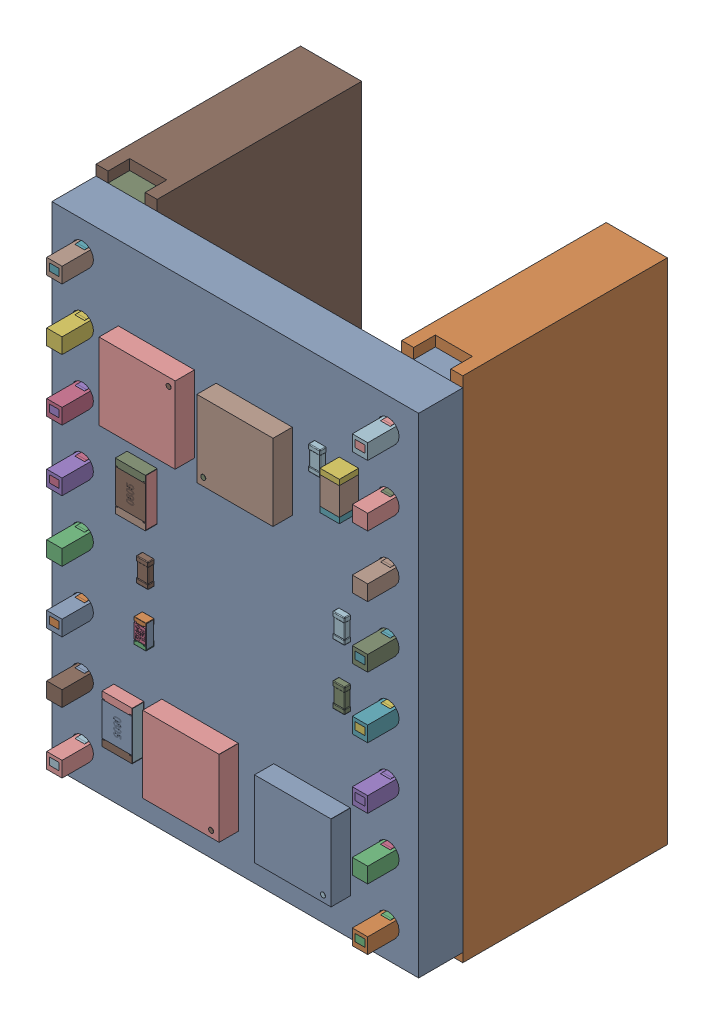
SolidWorks assembly MOTOR_DRIVER, configuration 默认. Lengths in mm.
Overall size (15.24 21.12 11.54).
82 component instances, 15 part files, 0 mates.
Components (placement in the parent):
- PCB-2-1: PCB-2 [默认] at (-7.62 10.26 8.5) x (1 0 0) z (0 0 -1) size (15.24 21.12 11.54)
  - Board-2-1: Board-2 [默认] at origin size (15.24 20.32 1.83)
    - Open CASCADE STEP translator 6.8 2.1.1-1: Open CASCADE STEP translator 6.8 2.1.1 [默认] at (0 0 -1.8339) size (15.24 20.32 1.83)
  - X-1: X [默认] at origin size (15.24 21.12 11.5)
    - DS1023-1x8SF11-1: DS1023-1x8SF11 [默认] at (13.9593 19.0061 0) x (0 -1 0) z (0 0 1) size (21.12 2.54 11.5)
    - DS1023-1x8SF11-2: DS1023-1x8SF11 [默认] at (1.2593 19.0061 0) x (0 -1 0) z (0 0 1) size (21.12 2.54 11.5)
  - U5-1: U5 [默认] at origin size (3.17 3.19 0.82)
    - 6641442208-1: 6641442208 [默认] at (8.4975 4.6 -2.7339) size (3.17 3.19 0.81)
      - Extruded-19-1: Extruded-19 [默认] at origin size (3.17 3.19 0.81)
    - 6641441808-1: 6641441808 [默认] at (7.1852 5.8608 -2.7339) x (0 -1 0) z (0 0 -1) size (0.2 0.2 0.01)
      - Cylinder-20-1: Cylinder-20 [默认] at origin size (0.2 0.2 0.01)
  - U1-1: U1 [默认] at origin size (3.19 3.17 0.82)
    - 6641441568-1: 6641441568 [默认] at (6.25 17.0875 -2.7339) size (3.19 3.17 0.81)
      - Extruded-21-1: Extruded-21 [默认] at origin size (3.19 3.17 0.81)
    - 6641441328-1: 6641441328 [默认] at (7.5108 18.3998 -2.7339) x (-1 0 0) z (0 0 -1) size (0.2 0.2 0.01)
      - Cylinder-22-1: Cylinder-22 [默认] at origin size (0.2 0.2 0.01)
  - C8-1: C8 [默认] at origin size (0.5 1 0.5)
    - User_Library-C0402-1-1: User_Library-C0402-1 [默认] at (11.385 3.6234 -1.8339) x (0 -1 0) z (0 0 -1) size (1 0.5 0.5)
  - R9-1: R9 [默认] at origin size (0.5 1 0.35)
    - User_Library-User_Library-RES0402-2-1: User_Library-User_Library-RES0402-2 [默认] at (3.9988 13.3623 -1.8339) x (0 1 0) z (0 0 -1) size (1 0.5 0.35)
  - R1-1: R1 [默认] at origin size (0.5 1 0.35)
    - User_Library-User_Library-RES0402-2-1: User_Library-User_Library-RES0402-2 [默认] at (3.1812 17.5123 0) x (0 1 0) z (0 0 1) size (1 0.5 0.35)
  - C3-1: C3 [默认] at origin size (0.5 1 0.5)
    - User_Library-C0402-1-1: User_Library-C0402-1 [默认] at (11.895 11.6466 -1.8339) x (0 1 0) z (0 0 -1) size (1 0.5 0.5)
  - U4-1: U4 [默认] at origin size (3.17 3.19 0.82)
    - 6641442208-1: 6641442208 [默认] at (4.4325 4.57 -2.7339) size (3.17 3.19 0.81)
      - Extruded-19-1: Extruded-19 [默认] at origin size (3.17 3.19 0.81)
    - 6641440128-1: 6641440128 [默认] at (5.7448 3.3092 -2.7339) x (0 1 0) z (0 0 -1) size (0.2 0.2 0.01)
      - Cylinder-23-1: Cylinder-23 [默认] at origin size (0.2 0.2 0.01)
  - U3-1: U3 [默认] at origin size (3.19 3.17 0.82)
    - 6641441328-1: 6641441328 [默认] at (12.1608 18.3998 -2.7339) x (-1 0 0) z (0 0 -1) size (0.2 0.2 0.01)
      - Cylinder-22-1: Cylinder-22 [默认] at origin size (0.2 0.2 0.01)
    - 6641441568-1: 6641441568 [默认] at (10.9 17.0875 -2.7339) size (3.19 3.17 0.81)
      - Extruded-21-1: Extruded-21 [默认] at origin size (3.19 3.17 0.81)
  - C1-1: C1 [默认] at origin size (0.5 1 0.5)
    - User_Library-C0402-1-1: User_Library-C0402-1 [默认] at (9.535 17.4466 0) x (0 1 0) z (0 0 1) size (1 0.5 0.5)
  - C2-1: C2 [默认] at origin size (1 0.5 0.5)
    - User_Library-C0402-1-1: User_Library-C0402-1 [默认] at (10.4533 16.155 0) x (-1 0 0) z (0 0 1) size (1 0.5 0.5)
  - C4-1: C4 [默认] at origin size (1 0.5 0.5)
    - User_Library-C0402-1-1: User_Library-C0402-1 [默认] at (7.7766 4.515 0) x (1 0 0) z (0 0 1) size (1 0.5 0.5)
  - C5-1: C5 [默认] at origin size (1 0.5 0.5)
    - User_Library-C0402-1-1: User_Library-C0402-1 [默认] at (11.2534 3.655 0) x (-1 0 0) z (0 0 1) size (1 0.5 0.5)
  - C7-1: C7 [默认] at origin size (0.81 1.6 0.8)
    - 6641443168-1: 6641443168 [默认] at (12.3314 3.3249 -2.6339) size (0.8 0.23 0.8)
      - Extruded-24-1: Extruded-24 [默认] at origin size (0.8 0.23 0.8)
    - 6641443168-2: 6641443168 [默认] at (12.3314 4.6949 -2.6339) size (0.8 0.23 0.8)
      - Extruded-24-1: Extruded-24 [默认] at origin size (0.8 0.23 0.8)
    - 6641442768-1: 6641442768 [默认] at (12.3313 4.0099 -2.6339) size (0.8 1.14 0.8)
      - Extruded-25-1: Extruded-25 [默认] at origin size (0.8 1.14 0.8)
  - C11-1: C11 [默认] at origin size (1 0.5 0.5)
    - User_Library-C0402-1-1: User_Library-C0402-1 [默认] at (6.8766 18.415 0) x (1 0 0) z (0 0 1) size (1 0.5 0.5)
  - C12-1: C12 [默认] at origin size (0.5 1 0.5)
    - User_Library-C0402-1-1: User_Library-C0402-1 [默认] at (3.095 3.6734 0) x (0 -1 0) z (0 0 1) size (1 0.5 0.5)
  - C13-1: C13 [默认] at origin size (0.5 1 0.5)
    - User_Library-C0402-1-1: User_Library-C0402-1 [默认] at (4.235 11.2234 -1.8339) x (0 -1 0) z (0 0 -1) size (1 0.5 0.5)
  - C14-1: C14 [默认] at origin size (0.5 1 0.5)
    - User_Library-C0402-1-1: User_Library-C0402-1 [默认] at (11.895 9.1466 -1.8339) x (0 1 0) z (0 0 -1) size (1 0.5 0.5)
  - C15-1: C15 [默认] at origin size (0.5 1 0.5)
    - User_Library-C0402-1-1: User_Library-C0402-1 [默认] at (12.485 4.8966 0) x (0 1 0) z (0 0 1) size (1 0.5 0.5)
  - J3-1: J3 [默认] at origin size (2.54 20.32 11.54)
    - 1001-8-1: 1001-8 [默认] at (1.259 19.037 0) x (0 -1 0) z (0 0 1) size (20.32 2.54 11.54)
  - J4-1: J4 [默认] at origin size (2.54 20.32 11.54)
    - 1001-8-1: 1001-8 [默认] at (13.959 19.037 0) x (0 -1 0) z (0 0 1) size (20.32 2.54 11.54)
  - R2-1: R2 [默认] at origin size (1.25 2 0.5)
    - User_Library-R_0805-1: User_Library-R_0805 [默认] at (3.19 17.0633 -1.8239) x (0 1 0) z (0 0 -1) size (2 1.25 0.5)
  - R3-1: R3 [默认] at origin size (0.5 1 0.35)
    - User_Library-User_Library-RES0402-2-1: User_Library-User_Library-RES0402-2 [默认] at (7.4488 17.1077 0) x (0 -1 0) z (0 0 1) size (1 0.5 0.35)
  - R4-1: R4 [默认] at origin size (1 0.5 0.35)
    - User_Library-User_Library-RES0402-2-1: User_Library-User_Library-RES0402-2 [默认] at (3.5377 15.3012 0) x (-1 0 0) z (0 0 1) size (1 0.5 0.35)
  - R6-1: R6 [默认] at origin size (0.5 1 0.35)
    - User_Library-User_Library-RES0402-2-1: User_Library-User_Library-RES0402-2 [默认] at (4.3312 17.5123 0) x (0 1 0) z (0 0 1) size (1 0.5 0.35)
  - R8-1: R8 [默认] at origin size (0.5 1 0.35)
    - User_Library-User_Library-RES0402-2-1: User_Library-User_Library-RES0402-2 [默认] at (6.2312 17.1123 0) x (0 1 0) z (0 0 1) size (1 0.5 0.35)
  - U2-1: U2 [默认] at origin size (8 8 1)
    - 6641437328-1: 6641437328 [默认] at (8.169 10.388 0) size (8 8 1)
      - Extruded-26-1: Extruded-26 [默认] at origin size (8 8 1)
    - 6641437008-1: 6641437008 [默认] at (11.439 13.736 0) x (0 -1 0) z (0 0 1) size (0.4 0.4 1)
      - Cylinder-27-1: Cylinder-27 [默认] at origin size (0.4 0.4 1)
  - R7-1: R7 [默认] at origin size (1.25 2 0.5)
    - User_Library-R_0805-1: User_Library-R_0805 [默认] at (3.74 8.4067 -1.8239) x (0 -1 0) z (0 0 -1) size (2 1.25 0.5)
  - C10-1: C10 [默认] at origin size (1 0.5 0.5)
    - User_Library-C0402-1-1: User_Library-C0402-1 [默认] at (9.0534 19.305 0) x (-1 0 0) z (0 0 1) size (1 0.5 0.5)
